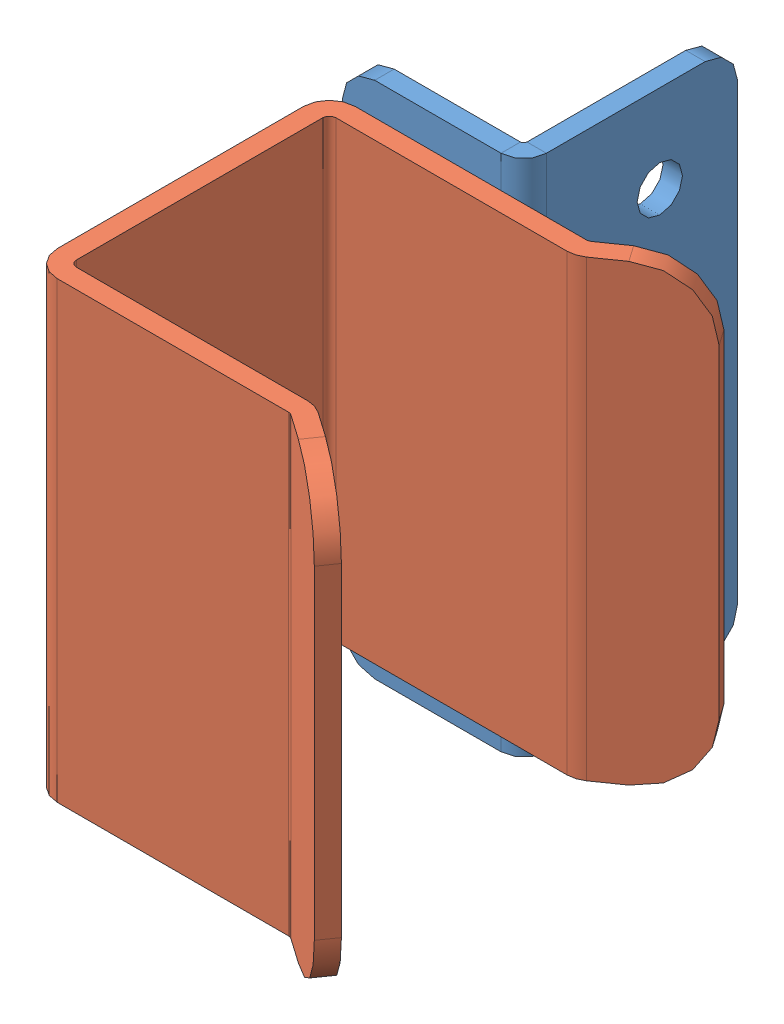
SolidWorks assembly A-0027956, configuration Default. Lengths in mm.
Overall size (54.01 80 87.6).
2 component instances, 2 part files, 0 mates.
Components (placement in the parent):
- A-0027749(Default)-1: A-0027749(Default) [Default] at (0 -40 -30) size (28 80 33)
- G2314-1-1-1: G2314-1-1 [Default] at (-27 0 26) size (54.01 70 63.21)
